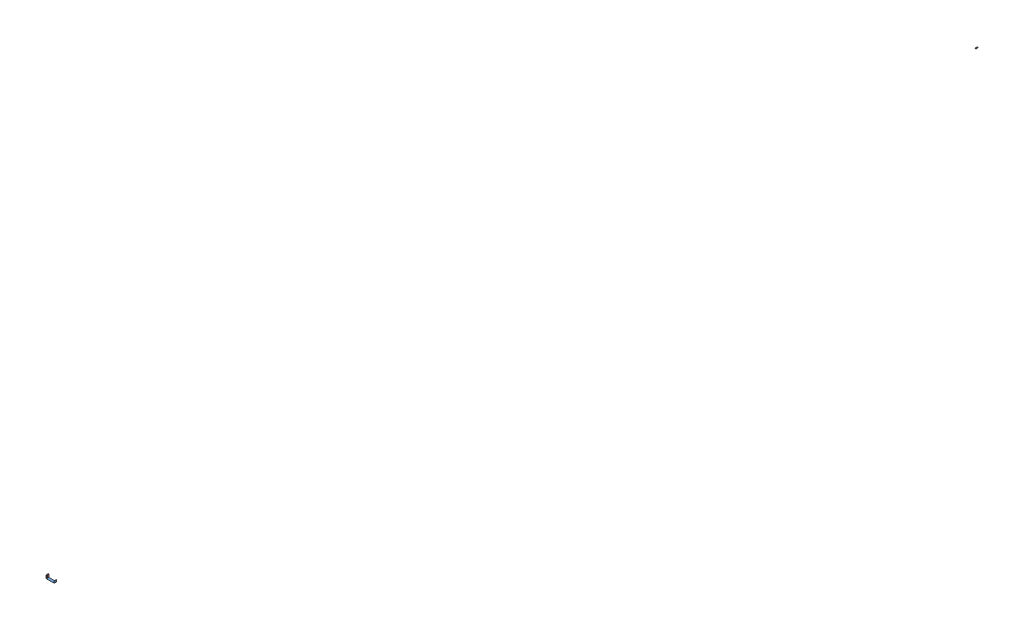
SolidWorks assembly 装配体1, configuration 默认. Lengths in mm.
Overall size (370 150.17 42096.49).
5 component instances, 5 part files, 8 mates.
Components (placement in the parent):
- 相机固定架-1: 相机固定架 [默认] at (-161.23 -66.7651 307.5) size (370 142 110)
- PCB版底座-1: PCB版底座 [默认] at (-126.23 12.904 357.4825) x (0 -1 0) z (1 0 0) size (122 103.2 35)
- fixbracket-1: fixbracket [默认] at (104.3609 -48.2651 -41653.5915) x (-0.020037 0 -0.999799) z (-0.999799 0 0.020037) size (29.3 31 32)
- Baslercamera-1: Baslercamera [默认] at (119.3919 -48.2651 -41627.2374) x (0 1 0) z (-0.020037 0 -0.999799) size (29.17 29.07 48.29)
- 镜头-1: 镜头 [默认] at (119.3919 -48.2651 -41627.2374) x (-0.616707 0.787095 0.01236) z (0.020037 0 0.999799) size (38 38 52.75)
Mates (geometry in assembly coordinates):
- 平行1: parallel anti-aligned: plane of 相机固定架-1 through (-161.23 -66.7651 307.5) normal (0 0 -1); plane of PCB版底座-1 through (-159.23 -48.096 415.6825) normal (0 0 1)
- 重合9: coincident anti-aligned: plane of 相机固定架-1 through (-159.23 -64.7651 417.5) normal (1 0 0); plane of PCB版底座-1 through (-159.23 12.904 357.4825) normal (-1 0 0)
- 重合10: coincident anti-aligned: plane of fixbracket-1 through (104.3609 -48.2651 -41653.5915) normal (0.999799 0 -0.020037); plane of Baslercamera-1 through (104.6544 -62.7101 -41638.9445) normal (-0.999799 0 0.020037)
- 平行2: parallel aligned: plane of fixbracket-1 through (102.6548 -33.7651 -41638.9044) normal (0 1 0); plane of Baslercamera-1 through (109.6395 -33.7651 -41641.1448) normal (0 1 0)
- 同心1: concentric anti-aligned: cylinder of fixbracket-1 through (104.5943 -38.2651 -41641.9439) axis (-0.999799 0 0.020037) radius 1.75; cylinder of Baslercamera-1 through (106.094 -38.2651 -41641.9739) axis (0.999799 0 -0.020037) radius 1.2293
- 重合11: coincident anti-aligned: plane of 相机固定架-1 through (-159.23 -64.7651 417.5) normal (0 1 0); plane of fixbracket-1 through (104.6544 -64.7651 -41638.9445) normal (0 -1 0)
- 同心2: concentric aligned: cylinder of Baslercamera-1 through (119.2958 -48.2651 -41632.0365) axis (-0.020037 0 -0.999799) radius 12.2682; cylinder of 镜头-1 through (120.4489 -48.2651 -41574.498) axis (-0.020037 0 -0.999799) radius 19
- 重合12: coincident anti-aligned: plane of Baslercamera-1 through (119.3919 -48.2651 -41627.2374) normal (0.020037 0 0.999799); plane of 镜头-1 through (119.3919 -48.2651 -41627.2374) normal (-0.020037 0 -0.999799)
